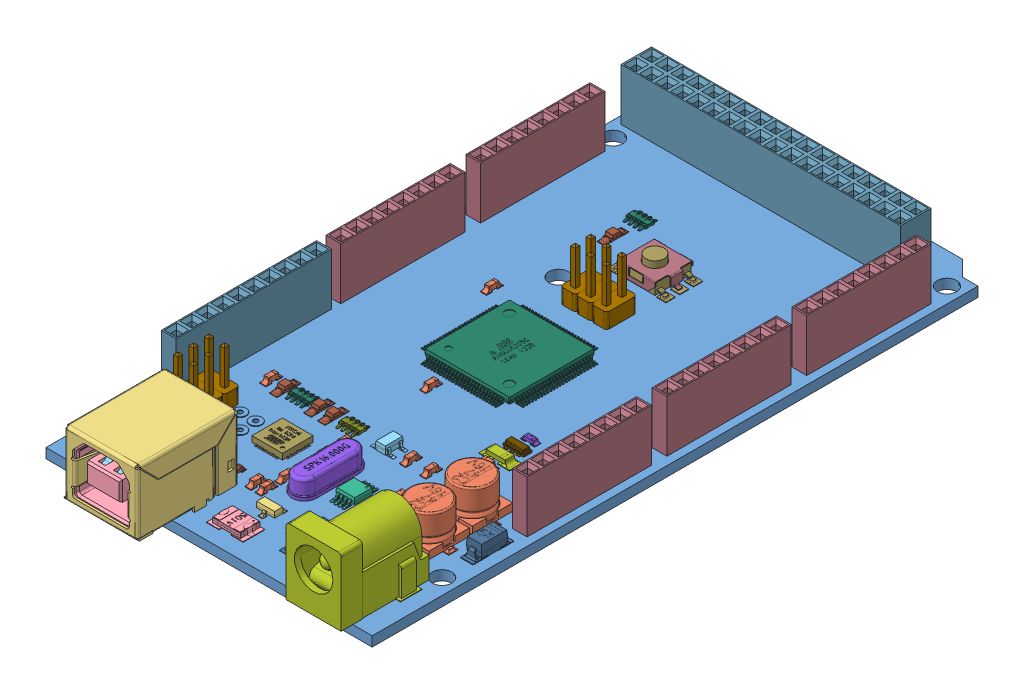
SolidWorks assembly arduino MEGA2650, configuration Default. Lengths in mm.
Overall size (53.34 15.25 107.99).
69 component instances, 33 part files, 170 mates.
Components (placement in the parent):
- MEGAboard-1: MEGAboard [Default] at origin size (53.34 1.6 101.6)
- 47uf CAP Dcase-1: 47uf CAP Dcase [Default] at (-9.144 0 -18.415) x (0 0 -1) z (1 0 0) size (6.6 5.81 8)
- USB type b-1: USB type b [Default] at (-38.02 0.43 6.35) size (14.34 15.2 16.54)
  - USB SHELL-1: USB SHELL [Default] at origin size (14.34 15.2 16.54)
  - USB core-1: USB core [Default] at origin size (11.3 10.68 15.75)
  - usb top contact-1: usb top contact [Default] at (1.25 6.09 -0.38) size (1 9.67 13.76)
  - usb btm contact-1: usb btm contact [Default] at (1.25 4.41 -0.38) size (1 6.84 11.76)
  - usb btm contact-2: usb btm contact [Default] at (-1.25 4.41 -0.38) size (1 6.84 11.76)
  - usb top contact-2: usb top contact [Default] at (-1.25 6.09 -0.38) size (1 9.67 13.76)
- power jack-1: power jack [Default] at (-7.675 0 1.905) size (11.2 15.2 15.9)
- 47uf CAP Dcase-2: 47uf CAP Dcase [Default] at (-9.144 0 -25.527) x (0 0 -1) z (1 0 0) size (6.6 5.81 8)
- crystal-1: crystal [Default] at (-26.035 0 -18.415) x (1 0 0) z (0 0 -1) size (4 5 11)
- 2pin_header__02-1: 2pin_header__02 [Default] at (-46.23 0 -15.75) size (5 11.75 2.54)
- reg-1: reg [Default] at (-17.78 0 -8.636) size (6.5 1.69 8.3)
- led-1: led [Default] at (-34.29 0 -27.94) x (0 0 1) z (-1 0 0) size (4 0.86 1.35)
- 2pin_header__02-2: 2pin_header__02 [Default] at (-30.43 0 -64.91) x (0 0 1) z (-1 0 0) size (5 11.75 2.54)
- 2pin_header__02-3: 2pin_header__02 [Default] at (-27.89 0 -64.91) x (0 0 1) z (-1 0 0) size (5 11.75 2.54)
- 2pin_header__02-4: 2pin_header__02 [Default] at (-25.35 0 -64.91) x (0 0 1) z (-1 0 0) size (5 11.75 2.54)
- 2pin_header__02-5: 2pin_header__02 [Default] at (-46.23 0 -18.29) size (5 11.75 2.54)
- 2pin_header__02-6: 2pin_header__02 [Default] at (-46.23 0 -20.83) size (5 11.75 2.54)
- atmega16u2-1: atmega16u2 [Default] at (-34.671 0.06 -20) x (1 0 0) z (0 0 -1) size (5.5 1.01 5.5)
- led-2: led [Default] at (-36.576 0 -27.94) x (0 0 -1) z (1 0 0) size (4 0.86 1.35)
- led-3: led [Default] at (-42.164 0 -27.94) x (0 0 1) z (-1 0 0) size (4 0.86 1.35)
- led-4: led [Default] at (-36.83 0 -76.2) x (0 0 1) z (-1 0 0) size (4 0.86 1.35)
- 8 PORT HEADER-3: 8 PORT HEADER [Default] at (-50.8 0 -45.72) x (0 0 -1) z (1 0 0) size (20.32 10.51 2.41)
- 8 PORT HEADER-4: 8 PORT HEADER [Default] at (-2.54 0 -27.94) x (0 0 -1) z (1 0 0) size (20.32 10.51 2.41)
- 8 PORT HEADER-6: 8 PORT HEADER [Default] at (-2.54 0 -50.8) x (0 0 -1) z (1 0 0) size (20.32 10.51 2.41)
- 10 PORT HEADER-1: 10 PORT HEADER [Default] at (-50.8 0 -18.796) x (0 0 -1) z (1 0 0) size (25.4 10.51 2.41)
- 102 RESISTOR PACK-1: 102 RESISTOR PACK [Default] at (-36.83 0 -80.645) size (3.2 0.46 3)
- 102 RESISTOR PACK-2: 102 RESISTOR PACK [Default] at (-39.37 0 -27.94) size (3.2 0.46 3)
- 103 RESISTOR PACK-3: 103 RESISTOR PACK [Default] at (-31.115 0 -27.94) size (3.2 0.46 3)
- 220 RESISTOR PACK-1: 220 RESISTOR PACK [Default] at (-37.084 0 -12.065) size (3.2 0.46 3)
- 16mhz crystal - measured-1: 16mhz crystal - measured [Default] at (-14.605 0 -38.354) size (3.4 0.8 2)
- PADS001-1: PADS001 [Default] at (-39.878 0.1 -18.288) x (-1 0 0) z (0 0 1) size (4.54 0.1 4.54)
- 603 cap on pad-1: 603 cap on pad [Default] at (-44.45 0 -27.94) x (0 0 -1) z (1 0 0) size (2.76 0.9 1.12)
- ssot3-1: ssot3 [Default] at (-25.908 0 -9.144) x (-1 0 0) z (0 0 -1) size (3 1.13 3.09)
- mf-msmf050-2-1: mf-msmf050-2 [Default] at (-26.67 0 -4.445) size (5.77 1.02 3.72)
- 603 cap on pad-2: 603 cap on pad [Default] at (-29.337 0 -24.765) x (0 0 1) z (-1 0 0) size (2.76 0.9 1.12)
- 603 cap on pad-3: 603 cap on pad [Default] at (-30.988 0 -12.065) x (0 0 -1) z (1 0 0) size (2.76 0.9 1.12)
- lmv358-1: lmv358 [Default] at (-25.146 0 -27.94) size (3.7 1.4 2.9)
- 603 cap on pad-4: 603 cap on pad [Default] at (-17.653 0 -14.351) size (2.76 0.9 1.12)
- 603 cap on pad-5: 603 cap on pad [Default] at (-29.337 0 -12.065) x (0 0 1) z (-1 0 0) size (2.76 0.9 1.12)
- 603 cap on pad-6: 603 cap on pad [Default] at (-29.337 0 -21.59) x (0 0 1) z (-1 0 0) size (2.76 0.9 1.12)
- 603 cap on pad-7: 603 cap on pad [Default] at (-29.337 0 -15.24) x (0 0 1) z (-1 0 0) size (2.76 0.9 1.12)
- 603 cap on pad-8: 603 cap on pad [Default] at (-42.291 0 -12.065) x (0 0 1) z (-1 0 0) size (2.76 0.9 1.12)
- lp2985dgkr-1: lp2985dgkr [Default] at (-21.336 0 -18.415) x (0 0 -1) z (1 0 0) size (5.85 1.1 3)
- cd1206 diode-1: cd1206 diode [Default] at (-14.605 0 -35.56) x (0 0 1) z (-1 0 0) size (2.07 0.96 5)
- cd1206 diode-2: cd1206 diode [Default] at (-46.228 0 -13.081) x (0 0 1) z (-1 0 0) size (2.07 0.96 5)
- 603 resistor-1: 603 resistor [Default] at (-29.337 0 -18.415) x (0 0 1) z (-1 0 0) size (2.36 0.61 1.03)
- blm21-1: blm21 [Default] at (-45.085 0 -8.255) x (0 0 -1) z (1 0 0) size (2.76 0.95 1.32)
- m7 diode-1: m7 diode [Default] at (-2.794 0 -21.59) x (0 0 -1) z (1 0 0) size (6.66 2.35 2.5)
- MLC0603-1: MLC0603 [Default] at (-34.29 0 -12.065) x (0 0 -1) z (1 0 0) size (2.36 0.6 1.03)
- MLC0603-2: MLC0603 [Default] at (-39.878 0 -12.065) x (0 0 -1) z (1 0 0) size (2.36 0.6 1.03)
- RESET BUTTON-1: RESET BUTTON [Default] at (-27.94 0 -74.168) x (0 0 -1) z (1 0 0) size (6.2 3.1 9.6)
  - RESET CORE-1: RESET CORE [Default] at (0 0.1 0) x (-1 0 0) z (0 0 -1) size (6.2 3.1 9.6)
  - RESET-1: RESET [Default] at (0 0.1 0) x (0 0 1) z (-1 0 0) size (7.3 2 6.2)
- 8 PORT HEADER-5: 8 PORT HEADER [Default] at (-2.54 0 -73.66) x (0 0 -1) z (1 0 0) size (20.32 10.51 2.41)
- 8 PORT HEADER-7: 8 PORT HEADER [Default] at (-50.8 0 -68.58) x (0 0 -1) z (1 0 0) size (20.32 10.51 2.41)
- 603 cap on pad-9: 603 cap on pad [Default] at (-21.59 0 -27.94) x (0 0 1) z (-1 0 0) size (2.76 0.9 1.12)
- 603 cap on pad-10: 603 cap on pad [Default] at (-18.288 0 -27.94) x (0 0 1) z (-1 0 0) size (2.76 0.9 1.12)
- 103 RESISTOR PACK-4: 103 RESISTOR PACK [Default] at (-16.51 0 -18.415) size (3.2 0.46 3)
- 603 cap on pad-11: 603 cap on pad [Default] at (-17.145 0 -21.59) x (0 0 -1) z (1 0 0) size (2.76 0.9 1.12)
- 603 cap on pad-12: 603 cap on pad [Default] at (-39.37 0 -58.928) x (0 0 1) z (-1 0 0) size (2.76 0.9 1.12)
- 603 cap on pad-13: 603 cap on pad [Default] at (-14.605 0 -33.528) size (2.76 0.9 1.12)
- 603 resistor-2: 603 resistor [Default] at (-14.605 0 -40.513) x (-1 0 0) z (0 0 -1) size (2.36 0.61 1.03)
- 603 cap on pad-14: 603 cap on pad [Default] at (-7.112 0 -38.608) x (0 0 1) z (-1 0 0) size (2.76 0.9 1.12)
- 603 cap on pad-15: 603 cap on pad [Default] at (-30.4038 0 -40.0558) x (0 0 1) z (-1 0 0) size (2.76 0.9 1.12)
- 18 X 2 ROW HEADER-1: 18 X 2 ROW HEADER [Default] at (-50.8 0 -95.25) size (45.72 10.51 4.95)
- atmega2650-16AU-1: atmega2650-16AU [Default] at (-28.3464 0.1 -50.8) x (0 0 1) z (-1 0 0) size (16.8 1.1 16.8)
Mates (geometry in assembly coordinates):
- Distance1: distance = 1.905 mm aligned: plane of power jack-1 through (-7.675 0 1.905) normal (0 0 1); plane of MEGAboard-1 through (0 0 0) normal (0 0 1)
- Coincident2: coincident aligned: plane of MEGAboard-1 through (0 0 0) normal (0 1 0); plane of power jack-1 through (-7.675 0 1.905) normal (0 1 0)
- Coincident3: coincident anti-aligned: plane of MEGAboard-1 through (0 0 0) normal (0 1 0); plane of USB type b-1/USB core-1 through (-38.02 0 6.35) normal (0 -1 0)
- Distance2: distance = 6.35 mm aligned: plane of USB type b-1/USB SHELL-1 through (-38.02 0.43 6.35) normal (0 0 1); plane of MEGAboard-1 through (0 0 0) normal (0 0 1)
- Coincident5: coincident aligned: plane of MEGAboard-1 through (0 0 0) normal (0 1 0); plane of 47uf CAP Dcase-1
- Parallel1: parallel anti-aligned: plane of MEGAboard-1 through (0 0 0) normal (0 0 1); plane of 47uf CAP Dcase-1 through (-9.144 0 -18.415) normal (0 0 -1)
- Coincident7: coincident aligned: plane of 47uf CAP Dcase-1 through (-5.844 1.5 -15.115) normal (1 0 0); plane of 47uf CAP Dcase-2 through (-5.844 1.5 -22.227) normal (1 0 0)
- Coincident8: coincident anti-aligned: plane of MEGAboard-1 through (0 0 0) normal (0 1 0); plane of 47uf CAP Dcase-2 through (-7.919 0 -25.527) normal (0 -1 0)
- Distance3: distance = 3.175 mm aligned: plane of power jack-1 through (-3.175 10.5 -1.595) normal (1 0 0); plane of MEGAboard-1 through (0 -1.6 0) normal (1 0 0)
- Distance4: distance = 32 mm aligned: plane of USB type b-1/USB SHELL-1 through (-32 0.43 6.35) normal (1 0 0); plane of MEGAboard-1 through (0 -1.6 0) normal (1 0 0)
- Coincident11: coincident anti-aligned: plane of MEGAboard-1 through (0 0 0) normal (0 1 0); plane of crystal-1 through (-26.035 0 -21.915) normal (0 -1 0)
- Concentric1: concentric aligned: cylinder of MEGAboard-1 through (-26.035 -10 -15.875) axis (0 1 0) radius 0.5; cylinder of crystal-1 through (-26.035 -2 -15.875) axis (0 1 0) radius 0.4
- Concentric2: concentric aligned: cylinder of MEGAboard-1 through (-26.035 -10 -20.955) axis (0 1 0) radius 0.5; cylinder of crystal-1 through (-26.035 -2 -20.955) axis (0 1 0) radius 0.4
- Coincident12: coincident anti-aligned: plane of MEGAboard-1 through (0 0 0) normal (0 1 0); plane of 2pin_header__02-1 through (-44.23 0 -14.98) normal (0 -1 0)
- Distance5: distance = 15.75 mm aligned: plane of 2pin_header__02-1 through (-46.23 0 -15.75) normal (0 0 1); plane of assembly through (0 0 0) normal (0 0 1)
- Distance6: distance = 46.23 mm aligned: plane of 2pin_header__02-1 through (-46.23 0 -15.75) normal (1 0 0); plane of assembly through (0 0 0) normal (1 0 0)
- Coincident15: coincident anti-aligned: plane of MEGAboard-1 through (0 0 0) normal (0 1 0); plane of 2pin_header__02-2 through (-31.2 0 -62.91) normal (0 -1 0)
- Distance7: distance = 64.91 mm aligned: plane of 2pin_header__02-2 through (-30.43 0 -64.91) normal (0 0 1); plane of assembly through (0 0 0) normal (0 0 1)
- Distance8: distance = 30.43 mm anti-aligned: plane of 2pin_header__02-2 through (-30.43 0 -64.91) normal (-1 0 0); plane of assembly through (0 0 0) normal (1 0 0)
- Coincident19: coincident anti-aligned: plane of MEGAboard-1 through (0 0 0) normal (0 1 0); plane of reg-1 through (-17.78 0 -8.636) normal (0 -1 0)
- Coincident21: coincident anti-aligned: plane of MEGAboard-1 through (0 0 0) normal (0 1 0); plane of atmega16u2-1 through (-34.671 0 -20) normal (0 -1 0)
- Distance10: distance = 20 mm anti-aligned: plane of atmega16u2-1 through (-34.671 0.06 -20) normal (0 0 -1); plane of MEGAboard-1 through (0 0 0) normal (0 0 1)
- Distance11: distance = 34.671 mm aligned: plane of atmega16u2-1; plane of MEGAboard-1 through (0 0 0) normal (1 0 0)
- Coincident25: coincident anti-aligned: plane of MEGAboard-1 through (0 0 0) normal (0 1 0); plane of led-1 through (-34.29 0 -28.94) normal (0 -1 0)
- Distance12: distance = 34.29 mm anti-aligned: plane of led-1 through (-34.29 0 -27.94) normal (-1 0 0); plane of MEGAboard-1 through (0 0 0) normal (1 0 0)
- Distance13: distance = 27.94 mm aligned: plane of led-1 through (-34.29 0 -27.94) normal (0 0 1); plane of MEGAboard-1 through (0 0 0) normal (0 0 1)
- Coincident28: coincident aligned: plane of led-2 through (-36.576 0 -26.94) normal (0 -1 0); plane of led-3 through (-42.164 0 -28.94) normal (0 -1 0)
- Coincident29: coincident anti-aligned: plane of led-1 through (-34.29 0 -27.94) normal (0 0 1); plane of led-2 through (-36.576 0 -27.94) normal (0 0 -1)
- Coincident30: coincident aligned: plane of led-1 through (-34.29 0 -27.94) normal (0 0 1); plane of led-3 through (-42.164 0 -27.94) normal (0 0 1)
- Distance14: distance = 36.576 mm aligned: plane of led-2 through (-36.576 0 -27.94) normal (1 0 0); plane of MEGAboard-1 through (0 0 0) normal (1 0 0)
- Coincident32: coincident anti-aligned: plane of MEGAboard-1 through (0 0 0) normal (0 1 0); plane of led-2 through (-36.576 0 -26.94) normal (0 -1 0)
- Distance15: distance = 42.164 mm anti-aligned: plane of led-3 through (-42.164 0 -27.94) normal (-1 0 0); plane of MEGAboard-1 through (0 0 0) normal (1 0 0)
- Coincident34: coincident anti-aligned: plane of MEGAboard-1 through (0 0 0) normal (0 1 0); plane of led-4 through (-36.83 0 -77.2) normal (0 -1 0)
- Distance16: distance = 36.83 mm anti-aligned: plane of led-4 through (-36.83 0 -76.2) normal (-1 0 0); plane of MEGAboard-1 through (0 0 0) normal (1 0 0)
- Distance17: distance = 76.2 mm aligned: plane of led-4 through (-36.83 0 -76.2) normal (0 0 1); plane of MEGAboard-1 through (0 0 0) normal (0 0 1)
- Coincident37: coincident aligned: plane of MEGAboard-1 through (0 0 0) normal (0 1 0); plane of 8 PORT HEADER-4
- Coincident38: coincident aligned: plane of MEGAboard-1 through (0 0 0) normal (0 1 0); plane of 8 PORT HEADER-3
- Parallel2: parallel aligned: plane of MEGAboard-1 through (0 0 0) normal (1 0 0); plane of 8 PORT HEADER-4 through (-2.54 0 -27.94) normal (1 0 0)
- Parallel3: parallel aligned: plane of MEGAboard-1 through (0 0 0) normal (1 0 0); plane of 8 PORT HEADER-3 through (-50.8 0 -45.72) normal (1 0 0)
- Concentric5: concentric aligned: cylinder of MEGAboard-1 through (-2.54 -1.65 -27.94) axis (0 1 0) radius 0.4; line of 8 PORT HEADER-4 through (-2.54 -2.5255 -27.94) axis (0 1 0)
- Concentric6: concentric aligned: cylinder of MEGAboard-1 through (-50.8 -1.65 -45.72) axis (0 1 0) radius 0.4; line of 8 PORT HEADER-3 through (-50.8 -2.5255 -45.72) axis (0 1 0)
- Coincident43: coincident aligned: plane of MEGAboard-1 through (0 0 0) normal (0 1 0); plane of 10 PORT HEADER-1
- Coincident44: coincident aligned: plane of MEGAboard-1 through (0 0 0) normal (0 1 0); plane of 8 PORT HEADER-6
- Parallel4: parallel aligned: plane of MEGAboard-1 through (0 0 0) normal (1 0 0); plane of 8 PORT HEADER-6 through (-2.54 0 -50.8) normal (1 0 0)
- Parallel5: parallel aligned: plane of MEGAboard-1 through (0 0 0) normal (1 0 0); plane of 10 PORT HEADER-1 through (-50.8 0 -18.796) normal (1 0 0)
- Concentric7: concentric aligned: cylinder of MEGAboard-1 through (-50.8 -1.65 -18.796) axis (0 1 0) radius 0.4; line of 10 PORT HEADER-1 through (-50.8 -2.5255 -18.796) axis (0 1 0)
- Concentric9: concentric aligned: cylinder of MEGAboard-1 through (-2.54 -1.65 -50.8) axis (0 1 0) radius 0.4; line of 8 PORT HEADER-6 through (-2.54 -2.5255 -50.8) axis (0 1 0)
- Distance18: distance = 8.636 mm: plane of reg-1 through (-17.78 0 -8.636) normal (0 0 1); line of MEGAboard-1 through (-53.34 0 0) axis (1 0 0)
- Distance19: distance = 17.78 mm aligned: plane of reg-1 through (-17.78 0 -8.636) normal (1 0 0); plane of MEGAboard-1 through (0 0 0) normal (1 0 0)
- Coincident55: coincident anti-aligned: plane of MEGAboard-1 through (0 0 0) normal (0 1 0); plane of 102 RESISTOR PACK-1 through (-37.03 0 -81.345) normal (0 -1 0)
- Distance20: distance = 36.83 mm aligned: plane of 102 RESISTOR PACK-1 through (-36.83 0 -80.645) normal (1 0 0); plane of MEGAboard-1 through (0 0 0) normal (1 0 0)
- Distance21: distance = 80.645 mm aligned: plane of 102 RESISTOR PACK-1 through (-36.83 0 -80.645) normal (0 0 1); plane of MEGAboard-1 through (0 0 0) normal (0 0 1)
- Coincident58: coincident aligned: plane of 102 RESISTOR PACK-2 through (-39.37 0 -27.94) normal (0 1 0); plane of 103 RESISTOR PACK-3 through (-31.115 0 -27.94) normal (0 1 0)
- Coincident59: coincident aligned: plane of MEGAboard-1 through (0 0 0) normal (0 1 0); plane of 103 RESISTOR PACK-3 through (-31.115 0 -27.94) normal (0 1 0)
- Coincident60: coincident aligned: plane of 102 RESISTOR PACK-2 through (-39.37 0 -27.94) normal (0 0 1); plane of 103 RESISTOR PACK-3 through (-31.115 0 -27.94) normal (0 0 1)
- Distance22: distance = 31.115 mm aligned: plane of 103 RESISTOR PACK-3 through (-31.115 0 -27.94) normal (1 0 0); plane of MEGAboard-1 through (0 0 0) normal (1 0 0)
- Distance23: distance = 39.37 mm aligned: plane of 102 RESISTOR PACK-2 through (-39.37 0 -27.94) normal (1 0 0); plane of MEGAboard-1 through (0 0 0) normal (1 0 0)
- Distance24: distance = 27.94 mm aligned: plane of 102 RESISTOR PACK-2 through (-39.37 0 -27.94) normal (0 0 1); plane of MEGAboard-1 through (0 0 0) normal (0 0 1)
- Distance25: distance = 12.065 mm aligned: plane of 220 RESISTOR PACK-1 through (-37.084 0 -12.065) normal (0 0 1); plane of MEGAboard-1 through (0 0 0) normal (0 0 1)
- Distance26: distance = 37.084 mm aligned: plane of 220 RESISTOR PACK-1 through (-37.084 0 -12.065) normal (1 0 0); plane of MEGAboard-1 through (0 0 0) normal (1 0 0)
- Coincident66: coincident aligned: plane of MEGAboard-1 through (0 0 0) normal (0 1 0); plane of 220 RESISTOR PACK-1 through (-37.084 0 -12.065) normal (0 1 0)
- Coincident67: coincident anti-aligned: plane of MEGAboard-1 through (0 0 0) normal (0 1 0); plane of 16mhz crystal - measured-1 through (-14.605 0 -38.354) normal (0 -1 0)
- Distance27: distance = 14.605 mm aligned: plane of 16mhz crystal - measured-1 through (-14.605 0 -38.354) normal (1 0 0); plane of MEGAboard-1 through (0 0 0) normal (1 0 0)
- Distance28: distance = 38.354 mm aligned: plane of 16mhz crystal - measured-1 through (-14.605 0 -38.354) normal (0 0 1); plane of MEGAboard-1 through (0 0 0) normal (0 0 1)
- Coincident70: coincident anti-aligned: plane of MEGAboard-1 through (0 0 0) normal (0 1 0); plane of PADS001-1 through (-42.418 0 -18.288) normal (0 -1 0)
- Distance29: distance = 18.288 mm aligned: plane of PADS001-1 through (-39.878 0.1 -18.288) normal (0 0 1); plane of MEGAboard-1 through (0 0 0) normal (0 0 1)
- Distance30: distance = 39.878 mm anti-aligned: plane of PADS001-1; plane of MEGAboard-1 through (0 0 0) normal (1 0 0)
- Distance31: distance = 4.445 mm aligned: plane of mf-msmf050-2-1 through (-26.67 0 -4.445) normal (0 0 1); plane of MEGAboard-1 through (0 0 0) normal (0 0 1)
- Distance32: distance = 26.67 mm aligned: plane of mf-msmf050-2-1 through (-26.67 0 -4.445) normal (1 0 0); plane of MEGAboard-1 through (0 0 0) normal (1 0 0)
- Coincident72: coincident aligned: plane of MEGAboard-1 through (0 0 0) normal (0 1 0); plane of mf-msmf050-2-1 through (-26.67 0 -4.445) normal (0 1 0)
- Distance33: distance = 9.144 mm anti-aligned: plane of MEGAboard-1 through (0 0 0) normal (0 0 1); plane of ssot3-1 through (-25.908 0 -9.144) normal (0 0 -1)
- Distance78: distance = 0.762 mm anti-aligned: plane of ssot3-1 through (-25.908 0 -9.144) normal (-1 0 0); plane of mf-msmf050-2-1 through (-26.67 0 -4.445) normal (1 0 0)
- Coincident75: coincident aligned: plane of MEGAboard-1 through (0 0 0) normal (0 1 0); plane of ssot3-1
- Coincident76: coincident anti-aligned: plane of led-1 through (-34.29 0 -27.94) normal (0 0 1); plane of 603 cap on pad-1 through (-44.45 0 -27.94) normal (0 0 -1)
- Coincident77: coincident aligned: plane of MEGAboard-1 through (0 0 0) normal (0 1 0); plane of 603 cap on pad-1
- Distance34: distance = 44.45 mm aligned: plane of 603 cap on pad-1 through (-44.45 0 -27.94) normal (1 0 0); plane of MEGAboard-1 through (0 0 0) normal (1 0 0)
- Coincident79: coincident aligned: plane of 603 cap on pad-2; plane of 603 cap on pad-3
- Coincident81: coincident aligned: plane of MEGAboard-1 through (0 0 0) normal (0 1 0); plane of 603 cap on pad-2
- Distance65: distance = 24.765 mm aligned: plane of 603 cap on pad-2 through (-29.337 0 -24.765) normal (0 0 1); plane of MEGAboard-1 through (0 0 0) normal (0 0 1)
- Distance36: distance = 29.337 mm anti-aligned: plane of 603 cap on pad-2 through (-29.337 0 -24.765) normal (-1 0 0); plane of MEGAboard-1 through (0 0 0) normal (1 0 0)
- Distance37: distance = 30.988 mm aligned: plane of 603 cap on pad-3 through (-30.988 0 -12.065) normal (1 0 0); plane of MEGAboard-1 through (0 0 0) normal (1 0 0)
- Distance38: distance = 27.94 mm aligned: plane of MEGAboard-1 through (0 0 0) normal (0 0 1); plane of lmv358-1 through (-25.146 0 -27.94) normal (0 0 1)
- Distance39: distance = 21.971 mm anti-aligned: plane of lmv358-1; plane of MEGAboard-1 through (0 0 0) normal (0 0 1)
- Coincident88: coincident aligned: plane of MEGAboard-1 through (0 0 0) normal (0 1 0); plane of lmv358-1 through (-25.146 0 -27.94) normal (0 1 0)
- Distance40: distance = 14.351 mm aligned: plane of 603 cap on pad-4 through (-17.653 0 -14.351) normal (0 0 1); plane of MEGAboard-1 through (0 0 0) normal (0 0 1)
- Distance41: distance = 17.653 mm aligned: plane of 603 cap on pad-4 through (-17.653 0 -14.351) normal (1 0 0); plane of MEGAboard-1 through (0 0 0) normal (1 0 0)
- Coincident91: coincident aligned: plane of MEGAboard-1 through (0 0 0) normal (0 1 0); plane of 603 cap on pad-4 through (-17.653 0 -14.351) normal (0 1 0)
- Coincident92: coincident aligned: plane of MEGAboard-1 through (0 0 0) normal (0 1 0); plane of 603 cap on pad-7
- Coincident93: coincident aligned: plane of MEGAboard-1 through (0 0 0) normal (0 1 0); plane of 603 cap on pad-6
- Coincident94: coincident aligned: plane of 603 cap on pad-5; plane of MEGAboard-1 through (0 0 0) normal (0 1 0)
- Coincident95: coincident aligned: plane of 603 cap on pad-8; plane of MEGAboard-1 through (0 0 0) normal (0 1 0)
- Coincident96: coincident aligned: plane of 603 cap on pad-7 through (-29.337 0 -15.24) normal (-1 0 0); plane of 603 cap on pad-6 through (-29.337 0 -21.59) normal (-1 0 0)
- Distance42: distance = 29.337 mm anti-aligned: plane of 603 cap on pad-7 through (-29.337 0 -15.24) normal (-1 0 0); plane of MEGAboard-1 through (0 0 0) normal (1 0 0)
- Distance43: distance = 21.59 mm: plane of 603 cap on pad-6 through (-29.337 0 -21.59) normal (0 0 1); line of MEGAboard-1 through (-53.34 0 0) axis (1 0 0)
- Distance44: distance = 15.24 mm aligned: plane of 603 cap on pad-7 through (-29.337 0 -15.24) normal (0 0 1); plane of MEGAboard-1 through (0 0 0) normal (0 0 1)
- Distance45: distance = 29.337 mm anti-aligned: plane of 603 cap on pad-5 through (-29.337 0 -12.065) normal (-1 0 0); plane of MEGAboard-1 through (0 0 0) normal (1 0 0)
- Distance46: distance = 12.065 mm aligned: plane of 603 cap on pad-5 through (-29.337 0 -12.065) normal (0 0 1); plane of MEGAboard-1 through (0 0 0) normal (0 0 1)
- Distance47: distance = 42.291 mm anti-aligned: plane of 603 cap on pad-8 through (-42.291 0 -12.065) normal (-1 0 0); plane of MEGAboard-1 through (0 0 0) normal (1 0 0)
- Distance48: distance = 12.065 mm aligned: plane of 603 cap on pad-8 through (-42.291 0 -12.065) normal (0 0 1); plane of MEGAboard-1 through (0 0 0) normal (0 0 1)
- Distance49: distance = 21.336 mm aligned: plane of lp2985dgkr-1 through (-21.336 0 -18.415) normal (1 0 0); plane of MEGAboard-1 through (0 0 0) normal (1 0 0)
- Distance50: distance = 18.415 mm anti-aligned: plane of lp2985dgkr-1 through (-21.336 0 -18.415) normal (0 0 -1); plane of MEGAboard-1 through (0 0 0) normal (0 0 1)
- Coincident99: coincident aligned: plane of MEGAboard-1 through (0 0 0) normal (0 1 0); plane of lp2985dgkr-1
- Distance51: distance = 14.605 mm anti-aligned: plane of cd1206 diode-1 through (-14.605 0 -35.56) normal (-1 0 0); plane of MEGAboard-1 through (0 0 0) normal (1 0 0)
- Distance52: distance = 35.56 mm aligned: plane of cd1206 diode-1 through (-14.605 0 -35.56) normal (0 0 1); plane of MEGAboard-1 through (0 0 0) normal (0 0 1)
- Coincident102: coincident aligned: plane of MEGAboard-1 through (0 0 0) normal (0 1 0); plane of cd1206 diode-1
- Distance53: distance = 46.228 mm anti-aligned: plane of cd1206 diode-2 through (-46.228 0 -13.081) normal (-1 0 0); plane of MEGAboard-1 through (0 0 0) normal (1 0 0)
- Distance54: distance = 13.081 mm aligned: plane of MEGAboard-1 through (0 0 0) normal (0 0 1); plane of cd1206 diode-2 through (-46.228 0 -13.081) normal (0 0 1)
- Coincident105: coincident aligned: plane of MEGAboard-1 through (0 0 0) normal (0 1 0); plane of cd1206 diode-2
- Distance55: distance = 29.337 mm anti-aligned: plane of 603 resistor-1 through (-29.337 0 -18.415) normal (-1 0 0); plane of MEGAboard-1 through (0 0 0) normal (1 0 0)
- Distance56: distance = 18.415 mm aligned: plane of 603 resistor-1 through (-29.337 0 -18.415) normal (0 0 1); plane of MEGAboard-1 through (0 0 0) normal (0 0 1)
- Coincident108: coincident aligned: plane of MEGAboard-1 through (0 0 0) normal (0 1 0); plane of 603 resistor-1
- Distance57: distance = 8.255 mm anti-aligned: plane of blm21-1 through (-45.085 0 -8.255) normal (0 0 -1); plane of MEGAboard-1 through (0 0 0) normal (0 0 1)
- Distance58: distance = 45.085 mm aligned: plane of blm21-1 through (-45.085 0 -8.255) normal (1 0 0); plane of MEGAboard-1 through (0 0 0) normal (1 0 0)
- Distance59: distance = 21.59 mm anti-aligned: plane of m7 diode-1 through (-2.794 0 -21.59) normal (0 0 -1); plane of MEGAboard-1 through (0 0 0) normal (0 0 1)
- Distance60: distance = 2.794 mm aligned: plane of m7 diode-1 through (-2.794 0 -21.59) normal (1 0 0); plane of MEGAboard-1 through (0 0 0) normal (1 0 0)
- Coincident113: coincident aligned: plane of MEGAboard-1 through (0 0 0) normal (0 1 0); plane of m7 diode-1
- Coincident114: coincident anti-aligned: plane of 220 RESISTOR PACK-1 through (-37.084 0 -12.065) normal (0 0 1); plane of MLC0603-1 through (-34.29 0 -12.065) normal (0 0 -1)
- Distance61: distance = 34.29 mm aligned: plane of MLC0603-1 through (-34.29 0 -12.065) normal (1 0 0); plane of MEGAboard-1 through (0 0 0) normal (1 0 0)
- Coincident115: coincident aligned: plane of MEGAboard-1 through (0 0 0) normal (0 1 0); plane of MLC0603-1
- Coincident116: coincident aligned: plane of MEGAboard-1 through (0 0 0) normal (0 1 0); plane of blm21-1
- Coincident117: coincident anti-aligned: plane of 220 RESISTOR PACK-1 through (-37.084 0 -12.065) normal (0 0 1); plane of MLC0603-2 through (-39.878 0 -12.065) normal (0 0 -1)
- Coincident118: coincident aligned: plane of MEGAboard-1 through (0 0 0) normal (0 1 0); plane of MLC0603-2
- Distance62: distance = 39.878 mm aligned: plane of MLC0603-2 through (-39.878 0 -12.065) normal (1 0 0); plane of MEGAboard-1 through (0 0 0) normal (1 0 0)
- Coincident122: coincident aligned: plane of MEGAboard-1 through (0 0 0) normal (0 1 0); plane of RESET BUTTON-1
- Concentric10: concentric aligned: cylinder of MEGAboard-1 through (-2.54 -1.65 -73.66) axis (0 1 0) radius 0.4; line of 8 PORT HEADER-5 through (-2.54 -2.5255 -73.66) axis (0 1 0)
- Coincident124: coincident anti-aligned: plane of MEGAboard-1 through (0 0 0) normal (0 1 0); plane of 8 PORT HEADER-5 through (-2.54 0 -73.66) normal (0 -1 0)
- Parallel6: parallel aligned: plane of MEGAboard-1 through (0 0 0) normal (1 0 0); plane of 8 PORT HEADER-5 through (-1.335 8.51 -72.39) normal (1 0 0)
- Concentric11: concentric aligned: cylinder of MEGAboard-1 through (-50.8 -1.65 -68.58) axis (0 1 0) radius 0.4; line of 8 PORT HEADER-7 through (-50.8 -2.5255 -68.58) axis (0 1 0)
- Parallel7: parallel aligned: plane of MEGAboard-1 through (0 0 0) normal (1 0 0); plane of 8 PORT HEADER-7 through (-49.595 8.51 -67.31) normal (1 0 0)
- Coincident128: coincident anti-aligned: plane of MEGAboard-1 through (0 0 0) normal (0 1 0); plane of 8 PORT HEADER-7 through (-50.8 0 -68.58) normal (0 -1 0)
- Distance63: distance = 27.94 mm aligned: plane of RESET BUTTON-1; plane of MEGAboard-1 through (0 0 0) normal (1 0 0)
- Distance64: distance = 74.168 mm anti-aligned: plane of RESET BUTTON-1 through (-27.94 0 -74.168) normal (0 0 -1); plane of MEGAboard-1 through (0 0 0) normal (0 0 1)
- Coincident131: coincident anti-aligned: plane of 603 cap on pad-3 through (-30.988 0 -12.065) normal (0 0 -1); plane of 603 cap on pad-5 through (-29.337 0 -12.065) normal (0 0 1)
- Distance66: distance = 25.146 mm aligned: plane of lmv358-1 through (-25.146 0 -27.94) normal (1 0 0); plane of MEGAboard-1 through (0 0 0) normal (1 0 0)
- Distance67: distance = 9.144 mm aligned: plane of 47uf CAP Dcase-2 through (-9.144 0 -25.527) normal (1 0 0); plane of MEGAboard-1 through (0 0 0) normal (1 0 0)
- Distance68: distance = 25.527 mm anti-aligned: plane of 47uf CAP Dcase-2 through (-9.144 0 -25.527) normal (0 0 -1); plane of MEGAboard-1 through (0 0 0) normal (0 0 1)
- Distance69: distance = 18.415 mm anti-aligned: plane of 47uf CAP Dcase-1 through (-9.144 0 -18.415) normal (0 0 -1); plane of MEGAboard-1 through (0 0 0) normal (0 0 1)
- Coincident136: coincident aligned: plane of 603 cap on pad-9 through (-21.59 0 -27.94) normal (0 0 1); plane of 603 cap on pad-10 through (-18.288 0 -27.94) normal (0 0 1)
- Distance72: distance = 3.302 mm aligned: plane of 603 cap on pad-9 through (-21.59 0 -27.94) normal (-1 0 0); plane of 603 cap on pad-10 through (-18.288 0 -27.94) normal (-1 0 0)
- Coincident143: coincident aligned: plane of 603 cap on pad-9; plane of 603 cap on pad-10
- Coincident144: coincident aligned: plane of MEGAboard-1 through (0 0 0) normal (0 1 0); plane of 603 cap on pad-9
- Coincident145: coincident anti-aligned: plane of 603 cap on pad-1 through (-44.45 0 -27.94) normal (0 0 -1); plane of 603 cap on pad-9 through (-21.59 0 -27.94) normal (0 0 1)
- Distance73: distance = 21.59 mm anti-aligned: plane of 603 cap on pad-9 through (-21.59 0 -27.94) normal (-1 0 0); plane of MEGAboard-1 through (0 0 0) normal (1 0 0)
- Coincident147: coincident aligned: plane of MEGAboard-1 through (0 0 0) normal (0 1 0); plane of 103 RESISTOR PACK-4 through (-16.51 0 -18.415) normal (0 1 0)
- Distance74: distance = 16.51 mm aligned: plane of 103 RESISTOR PACK-4 through (-16.51 0 -18.415) normal (1 0 0); plane of MEGAboard-1 through (0 0 0) normal (1 0 0)
- Distance75: distance = 18.415 mm aligned: plane of 103 RESISTOR PACK-4 through (-16.51 0 -18.415) normal (0 0 1); plane of MEGAboard-1 through (0 0 0) normal (0 0 1)
- Coincident150: coincident aligned: plane of MEGAboard-1 through (0 0 0) normal (0 1 0); plane of 603 cap on pad-11
- Distance76: distance = 17.145 mm aligned: plane of 603 cap on pad-11 through (-17.145 0 -21.59) normal (1 0 0); plane of MEGAboard-1 through (0 0 0) normal (1 0 0)
- Distance77: distance = 21.59 mm anti-aligned: plane of 603 cap on pad-11 through (-17.145 0 -21.59) normal (0 0 -1); plane of MEGAboard-1 through (0 0 0) normal (0 0 1)
- Coincident154: coincident aligned: plane of MEGAboard-1 through (0 0 0) normal (0 1 0); plane of 603 cap on pad-12
- Distance79: distance = 39.37 mm anti-aligned: plane of 603 cap on pad-12 through (-39.37 0 -58.928) normal (-1 0 0); plane of MEGAboard-1 through (0 0 0) normal (1 0 0)
- Distance80: distance = 58.928 mm aligned: plane of 603 cap on pad-12 through (-39.37 0 -58.928) normal (0 0 1); plane of MEGAboard-1 through (0 0 0) normal (0 0 1)
- Coincident155: coincident aligned: plane of 603 cap on pad-13 through (-14.605 0 -33.528) normal (0 1 0); plane of 603 resistor-2
- Coincident156: coincident anti-aligned: plane of 603 cap on pad-13 through (-14.605 0 -33.528) normal (1 0 0); plane of 603 resistor-2 through (-14.605 0 -40.513) normal (-1 0 0)
- Distance81: distance = 6.985 mm anti-aligned: plane of 603 cap on pad-13 through (-14.605 0 -33.528) normal (0 0 1); plane of 603 resistor-2 through (-14.605 0 -40.513) normal (0 0 -1)
- Distance82: distance = 33.528 mm aligned: plane of 603 cap on pad-13 through (-14.605 0 -33.528) normal (0 0 1); plane of MEGAboard-1 through (0 0 0) normal (0 0 1)
- Distance83: distance = 14.605 mm aligned: plane of 603 cap on pad-13 through (-14.605 0 -33.528) normal (1 0 0); plane of MEGAboard-1 through (0 0 0) normal (1 0 0)
- Coincident160: coincident aligned: plane of MEGAboard-1 through (0 0 0) normal (0 1 0); plane of 603 resistor-2
- Coincident161: coincident aligned: plane of MEGAboard-1 through (0 0 0) normal (0 1 0); plane of 603 cap on pad-14
- Distance84: distance = 7.112 mm anti-aligned: plane of 603 cap on pad-14 through (-7.112 0 -38.608) normal (-1 0 0); plane of MEGAboard-1 through (0 0 0) normal (1 0 0)
- Distance85: distance = 38.608 mm aligned: plane of 603 cap on pad-14 through (-7.112 0 -38.608) normal (0 0 1); plane of MEGAboard-1 through (0 0 0) normal (0 0 1)
- Coincident164: coincident aligned: plane of MEGAboard-1 through (0 0 0) normal (0 1 0); plane of 603 cap on pad-15
- Distance86: distance = 30.4038 mm anti-aligned: plane of 603 cap on pad-15 through (-30.4038 0 -40.0558) normal (-1 0 0); plane of MEGAboard-1 through (0 0 0) normal (1 0 0)
- Distance87: distance = 40.0558 mm aligned: plane of 603 cap on pad-15 through (-30.4038 0 -40.0558) normal (0 0 1); plane of MEGAboard-1 through (0 0 0) normal (0 0 1)
- Concentric12: concentric anti-aligned: cylinder of MEGAboard-1 through (-50.8 -10 -96.52) axis (0 1 0) radius 0.4; cylinder of 18 X 2 ROW HEADER-1 through (-50.8 -1.55 -96.52) axis (0 -1 0) radius 0.75
- Parallel8: parallel anti-aligned: plane of MEGAboard-1 through (0 0 0) normal (0 0 1); plane of 18 X 2 ROW HEADER-1 through (-52.07 8.51 -97.725) normal (0 0 -1)
- Coincident169: coincident anti-aligned: plane of MEGAboard-1 through (0 0 0) normal (0 1 0); plane of 18 X 2 ROW HEADER-1 through (-50.8 0 -95.25) normal (0 -1 0)
- Distance88: distance = 50.8 mm aligned: plane of MEGAboard-1 through (0 0 0) normal (0 0 1); plane of atmega2650-16AU-1 through (-28.3464 0.1 -50.8) normal (0 0 1)
- Distance89: distance = 28.3464 mm anti-aligned: plane of atmega2650-16AU-1 through (-28.3464 0.1 -50.8) normal (-1 0 0); plane of MEGAboard-1 through (0 0 0) normal (1 0 0)
- Coincident172: coincident anti-aligned: plane of MEGAboard-1 through (0 0 0) normal (0 1 0); plane of atmega2650-16AU-1 through (-35.3464 0 -49.15) normal (0 -1 0)
